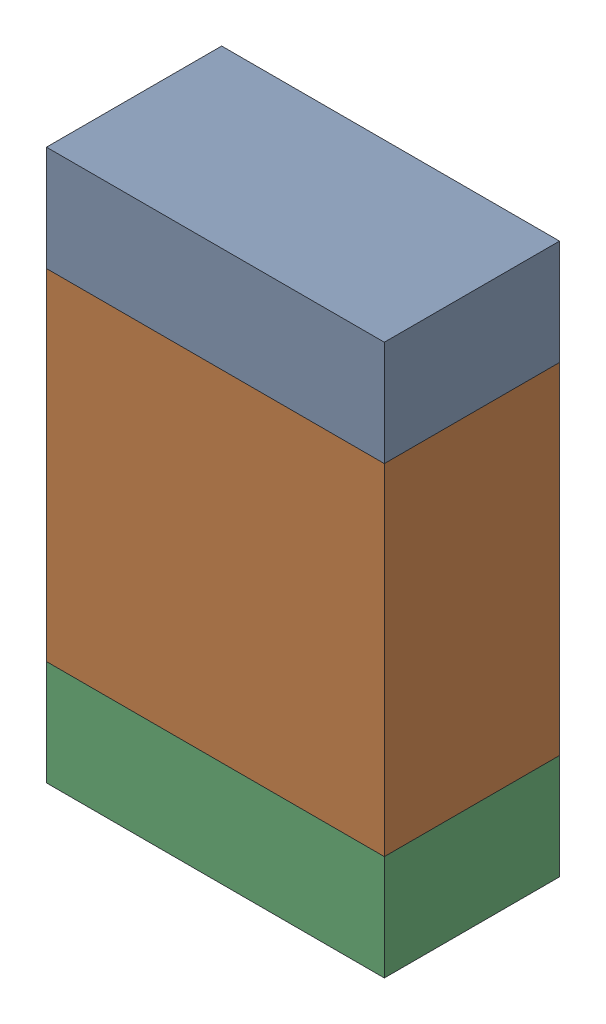
SolidWorks assembly R14-1, configuration Default. Lengths in mm.
Overall size (1.35 2.2 0.7).
6 component instances, 2 part files, 0 mates.
Components (placement in the parent):
- 959207304-1-1: 959207304-1 [Default] at (110.6132 93.495 0) size (1.35 0.42 0.7)
  - Extruded-39-1: Extruded-39 [Default] at origin size (1.35 0.42 0.7)
- 959207440-1-1: 959207440-1 [Default] at (110.6132 92.605 0) size (1.35 1.36 0.7)
  - Extruded-40-1: Extruded-40 [Default] at origin size (1.35 1.36 0.7)
- 959207304-1-2: 959207304-1 [Default] at (110.6132 91.715 0) size (1.35 0.42 0.7)
  - Extruded-39-1: Extruded-39 [Default] at origin size (1.35 0.42 0.7)
